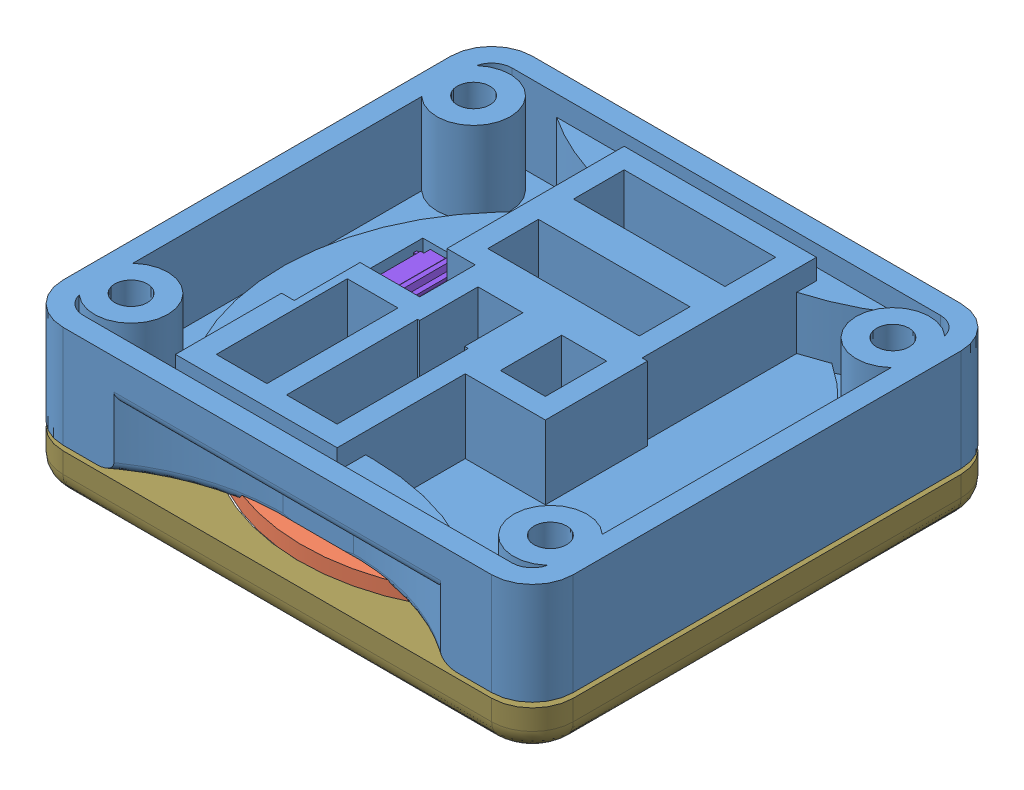
SolidWorks assembly Coin + Fixture, configuration Default. Lengths in mm.
Overall size (31.75 9.19 29.21).
228 component instances, 50 part files, 6 mates.
Components (placement in the parent):
- Holder - rev 6-1: Holder - rev 6 [Default] at (13.9059 11.132 24.9269) size (31.75 6.65 29.21)
- Biocoin_v1.3.step-1: Biocoin_v1.3.step [Default] at (0.9497 10.6797 11.9537) x (1 0 -0.000274) z (0 -1 0) size (24.9 26.1 4.91)
  - Board.step-1: Board.step [Default] at origin size (24.9 26.1 0.96)
    - Open CASCADE STEP translator 7.5 1.1.1.step-1: Open CASCADE STEP translator 7.5 1.1.1.step [Default] at (0 0 -0.9603) size (24.9 26.1 0.96)
  - R31.step-1: R31.step [Default] at origin size (0.64 0.33 0.33)
    - 6017375920.step-1: 6017375920.step [Default] at (6.6294 18.7198 0) x (-1 0 0) z (0 0 1) size (0.64 0.33 0.33)
  - R30.step-1: R30.step [Default] at origin size (0.33 0.64 0.33)
    - 6073967344.step-1: 6073967344.step [Default] at (1.8034 16.0528 0) x (0 -1 0) z (0 0 1) size (0.64 0.33 0.33)
  - Q4.step-1: Q4.step [Default] at origin size (1.04 0.61 0.54)
    - 6073960464.step-1: 6073960464.step [Default] at (6.3754 14.9606 0) size (1.04 0.61 0.54)
      - Body.step-1: Body.step [Default] at (0 0 0.1) size (1.01 0.61 0.44)
      - Pins.step-1: Pins.step [Default] at origin size (1.04 0.51 0.1)
  - RSENSE.step-1: RSENSE.step [Default] at origin size (0.6 1.04 0.34)
    - User Library-0402R.step-1: User Library-0402R.step [Default] at (4.7752 14.6813 0) x (0 1 0) z (1 0 0) size (1.04 0.34 0.6)
  - R29.step-1: R29.step [Default] at origin size (0.64 0.33 0.33)
    - 6017375920.step-1: 6017375920.step [Default] at (6.3754 16.1798 0) x (-1 0 0) z (0 0 1) size (0.64 0.33 0.33)
  - R28.step-1: R28.step [Default] at origin size (0.64 0.33 0.33)
    - 6073960624.step-1: 6073960624.step [Default] at (8.1026 14.4018 0) size (0.64 0.33 0.33)
  - R27.step-1: R27.step [Default] at origin size (0.64 0.33 0.33)
    - 6017375920.step-1: 6017375920.step [Default] at (8.1026 16.2052 0) x (-1 0 0) z (0 0 1) size (0.64 0.33 0.33)
  - R26.step-1: R26.step [Default] at origin size (0.6 1.04 0.34)
    - User Library-0402R.step-1: User Library-0402R.step [Default] at (4.7752 16.9753 0) x (0 1 0) z (1 0 0) size (1.04 0.34 0.6)
  - R25.step-1: R25.step [Default] at origin size (0.33 0.64 0.33)
    - 6073967344.step-1: 6073967344.step [Default] at (6.7818 12.3698 0) x (0 -1 0) z (0 0 1) size (0.64 0.33 0.33)
  - R24.step-1: R24.step [Default] at origin size (0.64 0.33 0.33)
    - 6017375920.step-1: 6017375920.step [Default] at (6.3754 13.7668 0) x (-1 0 0) z (0 0 1) size (0.64 0.33 0.33)
  - R23.step-1: R23.step [Default] at origin size (0.33 0.64 0.33)
    - 6073963104.step-1: 6073963104.step [Default] at (5.7658 12.3444 0) x (0 1 0) z (0 0 1) size (0.64 0.33 0.33)
  - R19.step-1: R19.step [Default] at origin size (0.64 0.33 0.33)
    - 6017375920.step-1: 6017375920.step [Default] at (3.0734 11.684 0) x (-1 0 0) z (0 0 1) size (0.64 0.33 0.33)
  - R12.step-1: R12.step [Default] at origin size (0.64 0.33 0.33)
    - 6073960624.step-1: 6073960624.step [Default] at (3.048 12.7254 0) size (0.64 0.33 0.33)
  - Q3.step-1: Q3.step [Default] at origin size (1 0.6 0.53)
    - 6073964224.step-1: 6073964224.step [Default] at (8.0558 17.399 0.03) x (1 0 0) z (0 -1 0) size (1 0.53 0.6)
  - Q2.step-1: Q2.step [Default] at origin size (1 0.6 0.53)
    - 6017376720.step-1: 6017376720.step [Default] at (6.3714 17.399 0.03) x (-1 0 0) z (0 1 0) size (1 0.53 0.6)
  - IC3.step-1: IC3.step [Default] at origin size (1 1.52 0.67)
    - 6073961504.step-1: 6073961504.step [Default] at (3.302 15.3924 0) x (0 1 0) z (0 0 1) size (1.52 1 0.67)
      - A1.step-1: A1.step [Default] at (-0.5 0.25 0.175) size (0.35 0.35 0.35)
      - A2.step-1: A2.step [Default] at (0 0.25 0.175) size (0.35 0.35 0.35)
      - A3.step-1: A3.step [Default] at (0.5 0.25 0.175) size (0.35 0.35 0.35)
      - B1.step-1: B1.step [Default] at (-0.5 -0.25 0.175) size (0.35 0.35 0.35)
      - B3.step-1: B3.step [Default] at (0.5 -0.25 0.175) size (0.35 0.35 0.35)
      - Body-0.step-1: Body-0.step [Default] at origin size (1.52 1 0.32)
  - IC2.step-1: IC2.step [Default] at origin size (2.1 2 1.1)
    - 6073963824.step-1: 6073963824.step [Default] at (5.6134 10.3124 0) x (-1 0 0) z (0 0 1) size (2.1 2 1.1)
      - Body-1.step-1: Body-1.step [Default] at origin size (1.25 2 1.05)
      - PinsArrayL.step-1: PinsArrayL.step [Default] at origin size (0.42 1.53 0.56)
      - PinsArrayR.step-1: PinsArrayR.step [Default] at origin size (0.42 1.53 0.56)
  - C39.step-1: C39.step [Default] at origin size (0.64 0.33 0.33)
    - 6017375920.step-1: 6017375920.step [Default] at (8.1026 15.2908 0) x (-1 0 0) z (0 0 1) size (0.64 0.33 0.33)
  - C38.step-1: C38.step [Default] at origin size (0.33 0.64 0.33)
    - 6073963104.step-1: 6073963104.step [Default] at (4.7752 12.3698 0) x (0 1 0) z (0 0 1) size (0.64 0.33 0.33)
  - C37.step-1: C37.step [Default] at origin size (0.64 0.33 0.33)
    - 6017375920.step-1: 6017375920.step [Default] at (3.0758 13.7179 0) x (-1 0 0) z (0 0 1) size (0.64 0.33 0.33)
  - U4.step-1: U4.step [Default] at origin size (1.5 1.5 0.4)
    - TLV8542RUGR.step-1: TLV8542RUGR.step [Default] at (8.4328 20.4216 0.0128) x (0 -1 0) z (-1 0 0) size (1.5 0.4 1.5)
  - R22.step-1: R22.step [Default] at origin size (0.33 0.64 0.33)
    - 6073967344.step-1: 6073967344.step [Default] at (10.1854 19.408 0) x (0 -1 0) z (0 0 1) size (0.64 0.33 0.33)
  - R21.step-1: R21.step [Default] at origin size (0.64 0.33 0.33)
    - 6017375920.step-1: 6017375920.step [Default] at (10.6426 20.7518 0) x (-1 0 0) z (0 0 1) size (0.64 0.33 0.33)
  - C34.step-1: C34.step [Default] at origin size (0.33 0.64 0.33)
    - 6073967344.step-1: 6073967344.step [Default] at (11.0744 19.408 0) x (0 -1 0) z (0 0 1) size (0.64 0.33 0.33)
  - C33.step-1: C33.step [Default] at origin size (0.64 0.33 0.33)
    - 6017375920.step-1: 6017375920.step [Default] at (12.2682 20.7518 0) x (-1 0 0) z (0 0 1) size (0.64 0.33 0.33)
  - L4.step-1: L4.step [Default] at origin size (0.64 0.33 0.33)
    - 6073960624.step-1: 6073960624.step [Default] at (8.128 18.7452 0) size (0.64 0.33 0.33)
  - R20.step-1: R20.step [Default] at origin size (0.33 0.64 0.33)
    - 6073967344.step-1: 6073967344.step [Default] at (1.7018 8.4328 0) x (0 -1 0) z (0 0 1) size (0.64 0.33 0.33)
  - R16.step-1: R16.step [Default] at origin size (0.64 0.33 0.33)
    - 6073960624.step-1: 6073960624.step [Default] at (5.0292 21.9456 0) size (0.64 0.33 0.33)
  - R15.step-1: R15.step [Default] at origin size (0.64 0.33 0.33)
    - 6017375920.step-1: 6017375920.step [Default] at (3.2004 19.8628 0) x (-1 0 0) z (0 0 1) size (0.64 0.33 0.33)
  - Q1.step-1: Q1.step [Default] at origin size (0.95 1.45 0.62)
    - 6073963584.step-1: 6073963584.step [Default] at (4.9276 19.3802 0) size (0.95 1.45 0.62)
      - Array.step-1: Array.step [Default] at origin size (0.81 1.31 0.31)
      - Body-2.step-1: Body-2.step [Default] at origin size (0.95 1.45 0.32)
  - L1.step-1: L1.step [Default] at origin size (2 2.5 1.2)
    - DFE252012F-100M=P2.step-1: DFE252012F-100M=P2.step [Default] at (5.4356 7.3152 0.0128) x (0 -1 0) z (-1 0 0) size (2.5 1.2 2)
  - C30.step-1: C30.step [Default] at origin size (0.64 0.33 0.33)
    - 6017375920.step-1: 6017375920.step [Default] at (3.2258 6.0198 0) x (-1 0 0) z (0 0 1) size (0.64 0.33 0.33)
  - C24.step-1: C24.step [Default] at origin size (1.05 0.51 0.51)
    - User Library-SMD Ceramic Capacitors_0402 (1005)_BB.step-1: User Library-SMD Ceramic Capacitors_0402 (1005)_BB.step [Default] at (7.972 6.1 0) x (-1 0 0) z (0 0 1) size (1.05 0.51 0.51)
  - J5.step-1: J5.step [Default] at origin size (3.6 11.7 1.9)
    - 503480-2000.step-1: 503480-2000.step [Default] at (1.5748 12.9794 -0.9731) x (0 1 0) z (-1 0 0) size (11.7 1.9 3.6)
      - Open CASCADE STEP translator 7.5 1.35.1.1.step-1: Open CASCADE STEP translator 7.5 1.35.1.1.step [Default] at origin size (11.7 1.9 3.6)
      - Open CASCADE STEP translator 7.5 1.35.1.2.step-1: Open CASCADE STEP translator 7.5 1.35.1.2.step [Default] at origin
  - R9.step-1: R9.step [Default] at origin size (0.64 0.33 0.33)
    - 6017375920.step-1: 6017375920.step [Default] at (5.0546 20.9804 0) x (-1 0 0) z (0 0 1) size (0.64 0.33 0.33)
  - R10.step-1: R10.step [Default] at origin size (0.33 0.64 0.33)
    - 6073967344.step-1: 6073967344.step [Default] at (6.604 19.9136 0) x (0 -1 0) z (0 0 1) size (0.64 0.33 0.33)
  - C28.step-1: C28.step [Default] at origin size (0.64 0.33 0.33)
    - 6017375920.step-1: 6017375920.step [Default] at (3.175 18.8468 0) x (-1 0 0) z (0 0 1) size (0.64 0.33 0.33)
  - IC1.step-1: IC1.step [Default] at origin size (1.77 1.77 0.5)
    - 6073966224.step-1: 6073966224.step [Default] at (11.049 6.223 0) x (0 1 0) z (0 0 1) size (1.77 1.77 0.5)
      - Array-3.step-1: Array-3.step [Default] at origin size (1.47 1.47 0.27)
      - Body-4.step-1: Body-4.step [Default] at origin size (1.77 1.77 0.23)
  - U2.step-1: U2.step [Default] at origin size (1.5 1.5 0.4)
    - TLV8542RUGR.step-1: TLV8542RUGR.step [Default] at (8.4328 23.0378 0.0128) x (0 -1 0) z (-1 0 0) size (1.5 0.4 1.5)
  - R18.step-1: R18.step [Default] at origin size (0.64 0.33 0.33)
    - 6073960624.step-1: 6073960624.step [Default] at (3.048 8.763 0) size (0.64 0.33 0.33)
  - R17.step-1: R17.step [Default] at origin size (0.33 0.64 0.33)
    - 6073967344.step-1: 6073967344.step [Default] at (14.8082 6.096 0) x (0 -1 0) z (0 0 1) size (0.64 0.33 0.33)
  - IC6.step-1: IC6.step [Default] at origin size (1.27 0.87 0.51)
    - IC_Maxim_Integrated_MAX17291ANT+T_eec.step-1: IC_Maxim_Integrated_MAX17291ANT+T_eec.step [Default] at (3.048 7.4676 0) x (-1 0 0) z (0 0 1) size (1.27 0.87 0.51)
      - 1.step-1: 1.step [Default] at (0 0 0.17) size (1.27 0.87 0.27)
      - 2.step-1: 2.step [Default] at (0 0 0.46) size (1.27 0.87 0.04)
      - 3.step-1: 3.step [Default] at (0 0 0.135) size (1.07 0.67 0.27)
      - Maxim Integrated Logo 1 - 1.step-1: Maxim Integrated Logo 1 - 1.step [Default] at (2.4226 -1.4739 0.401) size (1.14 0.74 0.11)
      - Maxim Integrated Logo 1.step-1: Maxim Integrated Logo 1.step [Default] at (1.1635 -2.318 0.401) size (0.12 0.12 0.1)
  - C36.step-1: C36.step [Default] at origin size (1.6 0.8 0.3)
    - SW3dPS-0603 SMD Capacitor.step-1: SW3dPS-0603 SMD Capacitor.step [Default] at (2.3369 10.2108 0) x (-1 0 0) z (0 1 0) size (1.6 0.3 0.8)
  - U8.step-1: U8.step [Default] at origin size (0.97 1.37 0.69)
    - 6073963184.step-1: 6073963184.step [Default] at (20.9042 6.477 0) size (0.97 1.37 0.69)
  - C32.step-1: C32.step [Default] at origin size (0.33 0.64 0.33)
    - 6073967344.step-1: 6073967344.step [Default] at (23.3172 6.6548 0) x (0 -1 0) z (0 0 1) size (0.64 0.33 0.33)
  - C31.step-1: C31.step [Default] at origin size (1.05 0.51 0.51)
    - User Library-SMD Ceramic Capacitors_0402 (1005)_BB.step-1: User Library-SMD Ceramic Capacitors_0402 (1005)_BB.step [Default] at (7.972 7.3192 0) x (-1 0 0) z (0 0 1) size (1.05 0.51 0.51)
  - U6.step-1: U6.step [Default] at origin size (1 1 0.36)
    - DQN0004A.step-1: DQN0004A.step [Default] at (3.1263 17.5361 0.0328) x (-1 0 0) z (0 1 0) size (1 0.36 1)
      - MOLD-SNB04A.step-1: MOLD-SNB04A.step [Default] at origin size (1 0.34 1)
      - FRAME-SNB04A.step-1: FRAME-SNB04A.step [Default] at (0 -0.02 0) size (1 0.11 1)
  - R14.step-1: R14.step [Default] at origin size (0.64 0.33 0.33)
    - 6073960624.step-1: 6073960624.step [Default] at (13.5128 6.1214 0) size (0.64 0.33 0.33)
  - C29.step-1: C29.step [Default] at origin size (0.33 0.64 0.33)
    - 6073963104.step-1: 6073963104.step [Default] at (1.778 17.5514 0) x (0 1 0) z (0 0 1) size (0.64 0.33 0.33)
  - R13.step-1: R13.step [Default] at origin size (1.04 0.6 0.34)
    - User Library-0402R.step-1: User Library-0402R.step [Default] at (16.3069 1.397 0) x (1 0 0) z (0 -1 0) size (1.04 0.34 0.6)
  - R8.step-1: R8.step [Default] at origin size (0.64 0.33 0.33)
    - 6017375920.step-1: 6017375920.step [Default] at (10.6426 22.7076 0) x (-1 0 0) z (0 0 1) size (0.64 0.33 0.33)
  - M2.step-1: M2.step [Default] at origin size (15.5 10.5 2.05)
    - MDBT50Q 3D Drawing_20180620_RGB8421504.step-1: MDBT50Q 3D Drawing_20180620_RGB8421504.step [Default] at (17.0122 12.9858 0.0128) x (0 -1 0) z (-1 0 0) size (10.5 2.05 15.5)
  - R11.step-1: R11.step [Default] at origin size (0.33 0.64 0.33)
    - 6073963104.step-1: 6073963104.step [Default] at (4.1656 4.6736 0) x (0 1 0) z (0 0 1) size (0.64 0.33 0.33)
  - C27.step-1: C27.step [Default] at origin size (0.64 0.33 0.33)
    - 6017375920.step-1: 6017375920.step [Default] at (12.2682 21.7424 0) x (-1 0 0) z (0 0 1) size (0.64 0.33 0.33)
  - C26.step-1: C26.step [Default] at origin size (0.64 0.33 0.33)
    - 6073960624.step-1: 6073960624.step [Default] at (6.1468 23.0632 0) size (0.64 0.33 0.33)
  - C25.step-1: C25.step [Default] at origin size (0.33 0.64 0.33)
    - 6073967344.step-1: 6073967344.step [Default] at (12.5984 25.1206 0) x (0 -1 0) z (0 0 1) size (0.64 0.33 0.33)
  - U3.step-1: U3.step [Default] at origin size (2.59 1.09 0.56)
    - 6073961184.step-1: 6073961184.step [Default] at (15.4003 24.6078 0) x (0 -1 0) z (0 0 1) size (1.09 2.59 0.56)
  - C13.step-1: C13.step [Default] at origin size (0.33 0.64 0.33)
    - 6073963104.step-1: 6073963104.step [Default] at (6.604 21.4884 0) x (0 1 0) z (0 0 1) size (0.64 0.33 0.33)
  - R7.step-1: R7.step [Default] at origin size (0.64 0.33 0.33)
    - 6017375920.step-1: 6017375920.step [Default] at (10.6426 21.7424 0) x (-1 0 0) z (0 0 1) size (0.64 0.33 0.33)
  - R5.step-1: R5.step [Default] at origin size (0.64 0.33 0.33)
    - 6017375920.step-1: 6017375920.step [Default] at (10.6426 23.5712 0) x (-1 0 0) z (0 0 1) size (0.64 0.33 0.33)
  - C12.step-1: C12.step [Default] at origin size (0.64 0.33 0.33)
    - 6017375920.step-1: 6017375920.step [Default] at (12.2682 23.5966 0) x (-1 0 0) z (0 0 1) size (0.64 0.33 0.33)
  - J2.step-1: J2.step [Default] at origin size (1.83 3.81 1)
    - 21120928.step-1: 21120928.step [Default] at (14.0716 2.4257 0) size (0.25 0.25 0.25)
      - Extruded.step-1: Extruded.step [Default] at origin size (0.25 0.25 0.25)
    - SDO_SOD-123FL_ONS.step-1: SDO_SOD-123FL_ONS.step [Default] at (13.9447 2.5526 0) x (0 1 0) z (0 0 1) size (3.81 1.83 1)
  - S1.step-1: S1.step [Default] at origin size (1.65 2.5 0.56)
    - 6017376320.step-1: 6017376320.step [Default] at (1.2192 13.3096 0) x (0 -1 0) z (0 0 1) size (2.5 1.65 0.56)
  - D1.step-1: D1.step [Default] at origin size (0.51 0.99 0.51)
    - 6073960224.step-1: 6073960224.step [Default] at (5.3086 4.064 0) x (0 1 0) z (0 0 1) size (0.99 0.51 0.51)
  - R6.step-1: R6.step [Default] at origin size (0.64 0.33 0.33)
    - 6073960624.step-1: 6073960624.step [Default] at (13.5128 6.9342 0) size (0.64 0.33 0.33)
  - L3.step-1: L3.step [Default] at origin size (2 1.6 1.2)
    - 6073968144.step-1: 6073968144.step [Default] at (11.1252 1.8542 0) x (-1 0 0) z (0 0 1) size (2 1.6 1.2)
      - term1.step-1: term1.step [Default] at (-1 -0.8 0) size (0.5 1.6 1.2)
      - term2.step-1: term2.step [Default] at (0.5 -0.8 0) size (0.5 1.6 1.2)
      - Body.step-1: Body.step [Default] at (-0.5 -0.784 0.012) size (1 1.57 1.18)
  - C23.step-1: C23.step [Default] at origin size (0.8 1.6 0.3)
    - SW3dPS-0603 SMD Capacitor.step-1: SW3dPS-0603 SMD Capacitor.step [Default] at (6.8834 3.4799 0) x (0 -1 0) z (-1 0 0) size (1.6 0.3 0.8)
  - C22.step-1: C22.step [Default] at origin size (0.8 1.6 0.3)
    - SW3dPS-0603 SMD Capacitor.step-1: SW3dPS-0603 SMD Capacitor.step [Default] at (8.6614 3.4799 0) x (0 -1 0) z (-1 0 0) size (1.6 0.3 0.8)
  - C21.step-1: C21.step [Default] at origin size (0.33 0.64 0.33)
    - 6073963104.step-1: 6073963104.step [Default] at (10.033 4.2672 0) x (0 1 0) z (0 0 1) size (0.64 0.33 0.33)
  - C20.step-1: C20.step [Default] at origin size (0.64 0.33 0.33)
    - 6073960624.step-1: 6073960624.step [Default] at (13.5382 5.2832 0) size (0.64 0.33 0.33)
  - C19.step-1: C19.step [Default] at origin size (1.05 0.51 0.51)
    - User Library-SMD Ceramic Capacitors_0402 (1005)_BB.step-1: User Library-SMD Ceramic Capacitors_0402 (1005)_BB.step [Default] at (11.7348 4.195 0) x (-1 0 0) z (0 0 1) size (1.05 0.51 0.51)
  - J1.step-1: J1.step [Default] at origin size (4.2 4.3 1.45)
    - 6073967584.step-1: 6073967584.step [Default] at (17.7292 4.699 0) x (1 0 0) z (0 -1 0) size (4.2 1.45 4.3)
  - U1.step-1: U1.step [Default] at origin size (4.19 3.61 0.56)
    - 6073961024.step-1: 6073961024.step [Default] at (15.8088 21.6742 0) size (4.19 3.61 0.56)
  - RTIA1.step-1: RTIA1.step [Default] at origin size (1.04 0.6 0.34)
    - User Library-0402R.step-1: User Library-0402R.step [Default] at (19.6151 22.6394 0) x (-1 0 0) z (0 1 0) size (1.04 0.34 0.6)
  - RCAL1.step-1: RCAL1.step [Default] at origin size (0.33 0.64 0.33)
    - 6073967344.step-1: 6073967344.step [Default] at (11.6586 25.019 0) x (0 -1 0) z (0 0 1) size (0.64 0.33 0.33)
  - R4.step-1: R4.step [Default] at origin size (0.64 0.33 0.33)
    - 6017375920.step-1: 6017375920.step [Default] at (9.3726 24.638 0) x (-1 0 0) z (0 0 1) size (0.64 0.33 0.33)
  - R3.step-1: R3.step [Default] at origin size (0.6 1.04 0.34)
    - User Library-0402R.step-1: User Library-0402R.step [Default] at (22.225 5.6133 0) x (0 -1 0) z (-1 0 0) size (1.04 0.34 0.6)
  - R2.step-1: R2.step [Default] at origin size (0.6 1.04 0.34)
    - User Library-0402R.step-1: User Library-0402R.step [Default] at (20.9296 4.2925 0) x (0 -1 0) z (-1 0 0) size (1.04 0.34 0.6)
  - R1.step-1: R1.step [Default] at origin size (0.64 0.33 0.33)
    - 6017375920.step-1: 6017375920.step [Default] at (8.1026 10.4648 0) x (-1 0 0) z (0 0 1) size (0.64 0.33 0.33)
  - CTIA1.step-1: CTIA1.step [Default] at origin size (1.05 0.51 0.51)
    - User Library-SMD Ceramic Capacitors_0402 (1005)_BB.step-1: User Library-SMD Ceramic Capacitors_0402 (1005)_BB.step [Default] at (19.6152 21.5004 0) x (-1 0 0) z (0 0 1) size (1.05 0.51 0.51)
  - CLPF1.step-1: CLPF1.step [Default] at origin size (0.33 0.64 0.33)
    - 6073963104.step-1: 6073963104.step [Default] at (10.8204 24.9936 0) x (0 1 0) z (0 0 1) size (0.64 0.33 0.33)
  - C18.step-1: C18.step [Default] at origin size (0.64 0.33 0.33)
    - 6017375920.step-1: 6017375920.step [Default] at (8.0772 8.636 0) x (-1 0 0) z (0 0 1) size (0.64 0.33 0.33)
  - C17.step-1: C17.step [Default] at origin size (0.64 0.33 0.33)
    - 6017375920.step-1: 6017375920.step [Default] at (8.0772 11.6078 0) x (-1 0 0) z (0 0 1) size (0.64 0.33 0.33)
  - C16.step-1: C16.step [Default] at origin size (0.51 1.05 0.51)
    - User Library-SMD Ceramic Capacitors_0402 (1005)_BB.step-1: User Library-SMD Ceramic Capacitors_0402 (1005)_BB.step [Default] at (8.1574 13.0302 0) x (0 1 0) z (0 0 1) size (1.05 0.51 0.51)
  - C15.step-1: C15.step [Default] at origin size (0.64 0.33 0.33)
    - 6017375920.step-1: 6017375920.step [Default] at (8.0772 9.5504 0) x (-1 0 0) z (0 0 1) size (0.64 0.33 0.33)
  - C14.step-1: C14.step [Default] at origin size (0.64 0.33 0.33)
    - 6017375920.step-1: 6017375920.step [Default] at (20.932 19.0754 0) x (-1 0 0) z (0 0 1) size (0.64 0.33 0.33)
  - C11.step-1: C11.step [Default] at origin size (1.05 0.51 0.51)
    - User Library-SMD Ceramic Capacitors_0402 (1005)_BB.step-1: User Library-SMD Ceramic Capacitors_0402 (1005)_BB.step [Default] at (19.6088 20.2558 0) x (-1 0 0) z (0 0 1) size (1.05 0.51 0.51)
  - C10.step-1: C10.step [Default] at origin size (0.64 0.33 0.33)
    - 6073960624.step-1: 6073960624.step [Default] at (12.2428 22.6822 0) size (0.64 0.33 0.33)
  - C9.step-1: C9.step [Default] at origin size (0.51 1.05 0.51)
    - User Library-SMD Ceramic Capacitors_0402 (1005)_BB.step-1: User Library-SMD Ceramic Capacitors_0402 (1005)_BB.step [Default] at (21.3146 20.7534 0) x (0 1 0) z (0 0 1) size (1.05 0.51 0.51)
  - C8.step-1: C8.step [Default] at origin size (0.64 0.33 0.33)
    - 6017375920.step-1: 6017375920.step [Default] at (19.05 23.6982 0) x (-1 0 0) z (0 0 1) size (0.64 0.33 0.33)
  - C7.step-1: C7.step [Default] at origin size (0.64 0.33 0.33)
    - 6017375920.step-1: 6017375920.step [Default] at (19.281 19.0754 0) x (-1 0 0) z (0 0 1) size (0.64 0.33 0.33)
  - C6.step-1: C6.step [Default] at origin size (0.64 0.33 0.33)
    - 6073960624.step-1: 6073960624.step [Default] at (16.0552 19.0754 0) size (0.64 0.33 0.33)
  - C5.step-1: C5.step [Default] at origin size (0.64 0.33 0.33)
    - 6017375920.step-1: 6017375920.step [Default] at (14.3534 19.0754 0) x (-1 0 0) z (0 0 1) size (0.64 0.33 0.33)
  - C4.step-1: C4.step [Default] at origin size (0.33 0.64 0.33)
    - 6073963104.step-1: 6073963104.step [Default] at (13.4112 25.1206 0) x (0 1 0) z (0 0 1) size (0.64 0.33 0.33)
  - C3.step-1: C3.step [Default] at origin size (0.33 0.64 0.33)
    - 6073967344.step-1: 6073967344.step [Default] at (11.9126 19.4334 0) x (0 -1 0) z (0 0 1) size (0.64 0.33 0.33)
  - C2.step-1: C2.step [Default] at origin size (0.33 0.64 0.33)
    - 6073967344.step-1: 6073967344.step [Default] at (12.7508 19.4334 0) x (0 -1 0) z (0 0 1) size (0.64 0.33 0.33)
  - C1.step-1: C1.step [Default] at origin size (0.64 0.33 0.33)
    - 6017375920.step-1: 6017375920.step [Default] at (17.5792 19.0754 0) x (-1 0 0) z (0 0 1) size (0.64 0.33 0.33)
- Holder Top - rev 3-1: Holder Top - rev 3 [Default] at (13.9059 10.8272 24.9269) x (1 0 0) z (0 0 -1) size (31.75 2.54 29.21)
Mates (geometry in assembly coordinates):
- Concentric8: concentric: cylinder of Holder - rev 6-1 through (22.6562 10.8272 21.1677) axis (0 1 0) radius 0.4763; circle of Biocoin_v1.3.step-1/Board.step-1/Open CASCADE STEP translator 7.5 1.1.1.step-1
- Parallel3: parallel: line of Holder - rev 6-1 through (25.7333 11.64 30.5149) axis (0 0 -1); line of Biocoin_v1.3.step-1/Board.step-1/Open CASCADE STEP translator 7.5 1.1.1.step-1 through (25.8008 11.64 19.4739) axis (0 0 1)
- Coincident3: coincident: plane of Holder - rev 6-1 through (13.9059 11.64 24.9269) normal (0 -1 0); plane of Biocoin_v1.3.step-1/Board.step-1/Open CASCADE STEP translator 7.5 1.1.1.step-1 through (14.5211 11.64 24.9444) normal (0 1 0)
- Concentric13: concentric aligned: circle of Holder - rev 6-1; circle of Holder Top - rev 3-1
- Concentric14: concentric aligned: circle of Holder - rev 6-1; circle of Holder Top - rev 3-1
- Parallel4: parallel anti-aligned: plane of Holder - rev 6-1 through (13.9059 11.132 24.9269) normal (0 -1 0); plane of Holder Top - rev 3-1 through (13.9059 10.8272 24.9269) normal (0 1 0)
